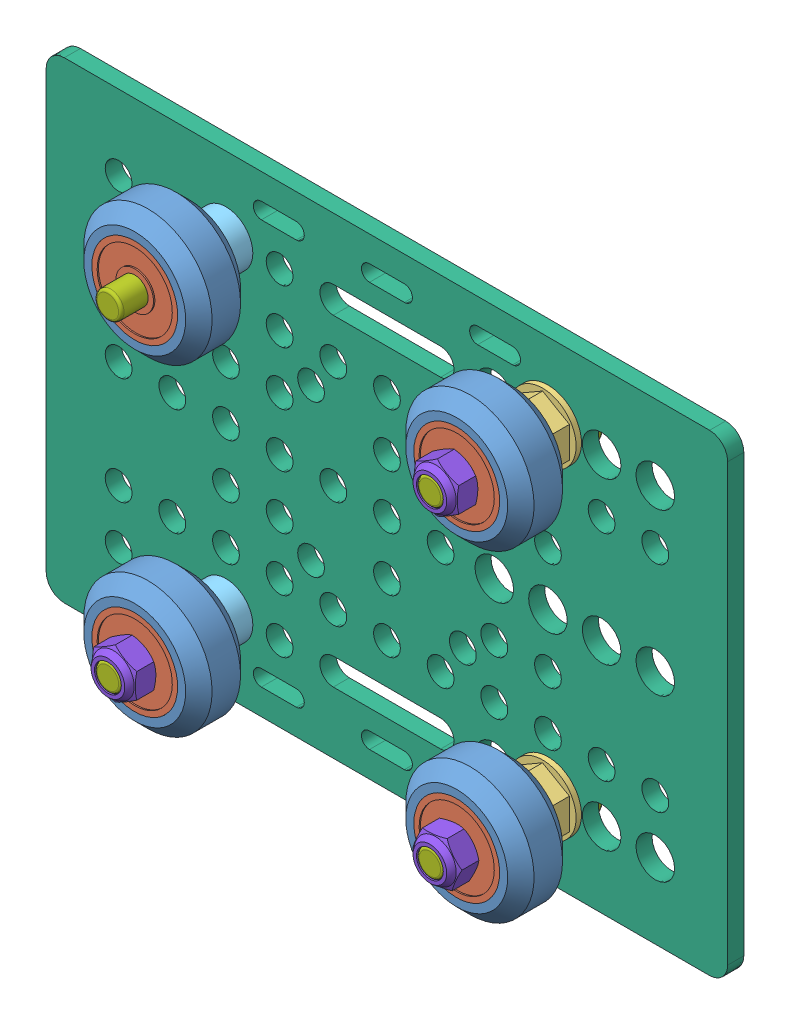
SolidWorks assembly 40mm Gantry Set universal, configuration Default. Lengths in mm.
Overall size (127 88 25).
34 component instances, 8 part files, 0 mates.
Components (placement in the parent):
- 40mm Gantry Set universal.stp-1: 40mm Gantry Set universal.stp [Default] at origin size (127 88 27)
  - V-Wheel Solid Wheel.stp-1: V-Wheel Solid Wheel.stp [Default] at (45.2695 32.9988 0.786) x (1 0 0) z (0 -1 0) size (23.9 20 23.9)
    - Solid V-Wheel.stp-1: Solid V-Wheel.stp [Default] at (-15.2695 -5.901 2.9988) size (23.9 10.23 23.9)
    - Ball Bearing 625 2RS 5x16x5.stp-1: Ball Bearing 625 2RS 5x16x5.stp [Default] at (-15.2695 -5.671 2.9988) x (1 0 0) z (0 1 0) size (16 16 5)
    - Ball Bearing 625 2RS 5x16x5.stp-2: Ball Bearing 625 2RS 5x16x5.stp [Default] at (-15.2695 -0.671 2.9988) x (0.579467 0 0.814996) z (0 1 0) size (16 16 5)
    - Eccentric Spacer.stp-1: Eccentric Spacer.stp [Default] at (-15.2695 -6.671 2.9988) x (1 0 0) z (0 -1 0) size (12.5 12.5 9)
    - 1mm 5mm shim.stp-1: 1mm 5mm shim.stp [Default] at (-15.2695 -5.671 2.9988) x (1 0 0) z (0 -1 0) size (10 10 1)
  - V-Wheel Solid Wheel.stp-2: V-Wheel Solid Wheel.stp [Default] at (45.2646 -26.9762 0.786) x (0.999999 0.00164 0) z (0.00164 -0.999999 0) size (23.9 20 23.9)
    - Solid V-Wheel.stp-1: Solid V-Wheel.stp [Default] at (-15.2695 -5.901 2.9988) size (23.9 10.23 23.9)
    - Ball Bearing 625 2RS 5x16x5.stp-1: Ball Bearing 625 2RS 5x16x5.stp [Default] at (-15.2695 -5.671 2.9988) x (1 0 0) z (0 1 0) size (16 16 5)
    - Ball Bearing 625 2RS 5x16x5.stp-2: Ball Bearing 625 2RS 5x16x5.stp [Default] at (-15.2695 -0.671 2.9988) x (0.579467 0 0.814996) z (0 1 0) size (16 16 5)
    - Eccentric Spacer.stp-1: Eccentric Spacer.stp [Default] at (-15.2695 -6.671 2.9988) x (1 0 0) z (0 -1 0) size (12.5 12.5 9)
    - 1mm 5mm shim.stp-1: 1mm 5mm shim.stp [Default] at (-15.2695 -5.671 2.9988) x (1 0 0) z (0 -1 0) size (10 10 1)
  - V-Wheel Solid Wheel - spacer.stp-1: V-Wheel Solid Wheel - spacer.stp [Default] at (-14.7305 -27.0012 0.786) x (1 0 0) z (0 -1 0) size (23.9 17 23.9)
    - Solid V-Wheel.stp-1: Solid V-Wheel.stp [Default] at (-15.2695 -5.901 2.9988) size (23.9 10.23 23.9)
    - Ball Bearing 625 2RS 5x16x5.stp-1: Ball Bearing 625 2RS 5x16x5.stp [Default] at (-15.2695 -5.671 2.9988) x (1 0 0) z (0 1 0) size (16 16 5)
    - Ball Bearing 625 2RS 5x16x5.stp-2: Ball Bearing 625 2RS 5x16x5.stp [Default] at (-15.2695 -0.671 2.9988) x (0.579467 0 0.814996) z (0 1 0) size (16 16 5)
    - 1mm 5mm shim.stp-1: 1mm 5mm shim.stp [Default] at (-15.2695 -5.671 2.9988) x (1 0 0) z (0 -1 0) size (10 10 1)
    - 6mm Spacer.stp-1: 6mm Spacer.stp [Default] at (-15.2695 -6.671 2.9988) x (1 0 0) z (0 -1 0) size (10 10 6)
  - V-Wheel Solid Wheel - spacer.stp-2: V-Wheel Solid Wheel - spacer.stp [Default] at (-14.7305 32.9988 0.786) x (1 0 0) z (0 -1 0) size (23.9 17 23.9)
    - Solid V-Wheel.stp-1: Solid V-Wheel.stp [Default] at (-15.2695 -5.901 2.9988) size (23.9 10.23 23.9)
    - Ball Bearing 625 2RS 5x16x5.stp-1: Ball Bearing 625 2RS 5x16x5.stp [Default] at (-15.2695 -5.671 2.9988) x (1 0 0) z (0 1 0) size (16 16 5)
    - Ball Bearing 625 2RS 5x16x5.stp-2: Ball Bearing 625 2RS 5x16x5.stp [Default] at (-15.2695 -0.671 2.9988) x (0.579467 0 0.814996) z (0 1 0) size (16 16 5)
    - 1mm 5mm shim.stp-1: 1mm 5mm shim.stp [Default] at (-15.2695 -5.671 2.9988) x (1 0 0) z (0 -1 0) size (10 10 1)
    - 6mm Spacer.stp-1: 6mm Spacer.stp [Default] at (-15.2695 -6.671 2.9988) x (1 0 0) z (0 -1 0) size (10 10 6)
  - 80mm gantry plate.stp-1: 80mm gantry plate.stp [Default] at (0 0 -14.885) size (127 88 3)
  - M5x25 low profile screw.stp-1: M5x25 low profile screw.stp [Default] at (-30 -30 -16.885) size (11 11 27)
  - M5x25 low profile screw.stp-2: M5x25 low profile screw.stp [Default] at (-30 30 -16.885) size (11 11 27)
  - M5x25 low profile screw.stp-3: M5x25 low profile screw.stp [Default] at (30 30 -16.885) size (11 11 27)
  - M5x25 low profile screw.stp-4: M5x25 low profile screw.stp [Default] at (30 -30 -16.885) size (11 11 27)
  - M5 Nylock.stp-1: M5 Nylock.stp [Default] at (-30 -30 5.115) size (9.24 9.25 5)
  - M5 Nylock.stp-2: M5 Nylock.stp [Default] at (-30 30 5.115) x (-0.944987 -0.327107 0) z (0 0 1) size (9.24 9.25 5) (hidden)
  - M5 Nylock.stp-3: M5 Nylock.stp [Default] at (30 30 5.115) size (9.24 9.25 5)
  - M5 Nylock.stp-4: M5 Nylock.stp [Default] at (30 -30 5.115) x (-0.800482 -0.599357 0) z (0 0 1) size (9.24 9.25 5)
